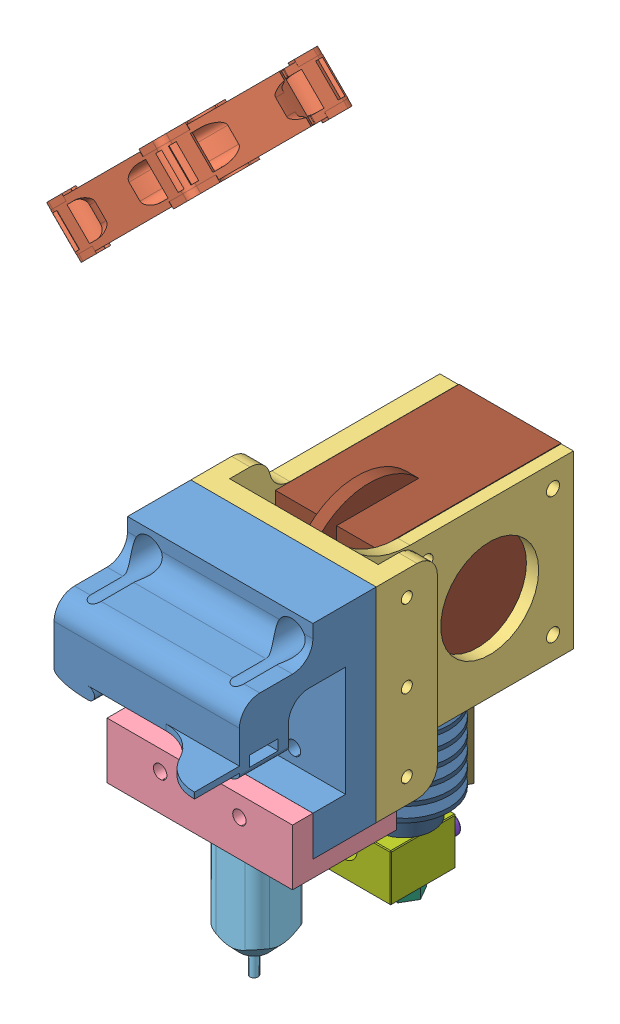
SolidWorks assembly Extruder Assembly, configuration Default. Lengths in mm.
Overall size (127.5 148.89 106).
17 component instances, 13 part files, 15 mates.
Components (placement in the parent):
- X Carriege Tool Mount-1: X Carriege Tool Mount [Default] at (45.4 75.1817 183.5817) x (-1 0 0) z (0 0 -1) size (45.42 50 44.5)
- Noctua-NF-A4x10-1: Noctua-NF-A4x10 [Default] at (-36.401 156.8138 129.5886) x (0 0 1) z (0.707107 -0.707107 0) size (40.06 40.06 12.26)
- Nema 17-1: Nema 17 [Default] at (72.7 96.1817 127.5817) x (0 1 0) z (-1 0 0) size (42 42 61)
- TItan Extruder Mount Simple v1-1: TItan Extruder Mount Simple v1 [Default] at (45.4 75.1817 168.0817) x (-1 0 0) z (0 0 -1) size (45.4 50 61)
- BL Touch Mount-1: BL Touch Mount [Default] at (-27.8645 -78.7405 -106.5513) size (45.4 56.15 32.72)
  - BL Touch Mount v2-1: BL Touch Mount v2 [Default] at (27.8645 153.9222 269.633) x (1 0 0) z (0 0 -1) size (45.4 13.75 25.5)
  - BL-touch-1: BL-touch [Predeterminado] at (44.1413 149.9222 275.4167) x (-1 0 0) z (0 1 0) size (26 26 42.4)
- E3D Titan Extruder-1: E3D Titan Extruder [Default] at (87.1521 59.5503 115.323) x (0 0 1) z (-1 0 0) size (54 96.06 28.75)
  - p_E3D.V6-1.75mm_0.3Nozzle_wPushIn_Bowden_-1: p_E3D.V6-1.75mm_0.3Nozzle_wPushIn_Bowden_ [Défaut] at (16.7586 -33.2186 70.9521) x (0 0 1) z (-1 0 0) size (27.2 60.7 23.91)
    - Nozzle 0.3mm^p_E3D.V6-1.75mm_0.3Nozzle_wPushIn_Bowden_-1: Nozzle 0.3mm^p_E3D.V6-1.75mm_0.3Nozzle_wPushIn_Bowden_ [Défaut] at origin size (8.08 13.04 7) (virtual)
    - Heater_Block^p_E3D.V6-1.75mm_0.3Nozzle_wPushIn_Bowden_-1: Heater_Block^p_E3D.V6-1.75mm_0.3Nozzle_wPushIn_Bowden_ [Défaut] at (0 5 0) x (1 0 0) z (0 1 0) size (20 16 11.5) (virtual)
    - socket head cap screw_din-3: socket head cap screw_din [DIN 912 M2 x 12 --- 12C] at (13.25 3 0) x (0 1 0) z (0 0 1) size (14 3.8 3.8)
    - socket head cap screw_din-4: socket head cap screw_din [DIN 912 M2.5 x 4 --- 4C] at (-1.25 11.5 10.5) x (0 0 -1) z (1 0 0) size (6.5 4.5 4.5)
    - Heatbreak^p_E3D.V6-1.75mm_0.3Nozzle_wPushIn_Bowden_-1: Heatbreak^p_E3D.V6-1.75mm_0.3Nozzle_wPushIn_Bowden_ [Défaut] at (0 12.5 0) x (0.99999 0 0.004447) z (-0.004447 0 0.99999) size (7.01 23.53 7.2) (virtual)
    - Heatsink^p_E3D.V6-1.75mm_0.3Nozzle_wPushIn_Bowden_-1: Heatsink^p_E3D.V6-1.75mm_0.3Nozzle_wPushIn_Bowden_ [Défaut] at (0 60.7 0) x (-0.995869 0 -0.090804) z (-0.090804 0 0.995869) size (22 42.7 22) (virtual)
  - Extruder Block-1: Extruder Block [Default] at (14.2586 36.7814 57.4521) size (54 47.06 25)
- Cooling Fan Mount v1-1: Cooling Fan Mount v1 [Default] at (16.2 48.6639 132.0817) x (-1 0 0) z (0 0 -1) size (25.84 41.08 40)
Mates (geometry in assembly coordinates):
- Coincident408: coincident anti-aligned: plane of X Carriege Tool Mount-1 through (45.4 75.1817 168.0817) normal (0 0 -1); plane of TItan Extruder Mount Simple v1-1 through (45.4 75.1817 168.0817) normal (0 0 1)
- Concentric134: concentric aligned: cylinder of X Carriege Tool Mount-1 through (40.2 120.1817 212.5817) axis (0 0 -1) radius 1.7; cylinder of TItan Extruder Mount Simple v1-1 through (40.2 120.1817 173.0817) axis (0 0 -1) radius 1.35
- Concentric135: concentric aligned: cylinder of X Carriege Tool Mount-1 through (5.2 120.1817 212.5817) axis (0 0 -1) radius 1.7; cylinder of TItan Extruder Mount Simple v1-1 through (5.2 120.1817 173.0817) axis (0 0 -1) radius 1.35
- Coincident414: coincident anti-aligned: plane of Nema 17 Small-1 through (32.7 96.1817 127.5817) normal (-1 0 0); plane of TItan Extruder Mount Simple v1-1 through (32.7 75.1817 107.0817) normal (1 0 0)
- Concentric136: concentric anti-aligned: cylinder of Nema 17 Small-1 through (72.7 80.6817 112.0817) axis (-1 0 0) radius 1.5; cylinder of TItan Extruder Mount Simple v1-1 through (-9.3 80.6817 112.0817) axis (1 0 0) radius 1.6
- Concentric137: concentric anti-aligned: cylinder of Nema 17 Small-1 through (72.7 111.6817 143.0817) axis (-1 0 0) radius 1.5; cylinder of TItan Extruder Mount Simple v1-1 through (-9.3 111.6817 143.0817) axis (1 0 0) radius 1.6
- Coincident409: coincident anti-aligned: plane of X Carriege Tool Mount-1 through (45.4 75.1817 183.5817) normal (0 0 1); plane of BL Touch Mount-1/BL Touch Mount v2-1 through (45.4 84.9317 183.5817) normal (0 0 -1)
- Coincident410: coincident anti-aligned: plane of X Carriege Tool Mount-1 through (45.4 75.1817 168.0817) normal (0 -1 0); plane of BL Touch Mount-1/BL Touch Mount v2-1 through (0 75.1817 163.0817) normal (0 1 0)
- Coincident411: coincident aligned: plane of X Carriege Tool Mount-1 through (0 75.1817 168.0817) normal (-1 0 0); plane of BL Touch Mount-1/BL Touch Mount v2-1 through (0 71.1817 163.0817) normal (-1 0 0)
- Coincident415: coincident anti-aligned: plane of E3D Titan Extruder-1/Extruder Block-1 through (29.7 96.3317 129.5817) normal (1 0 0); plane of TItan Extruder Mount Simple v1-1 through (29.7 75.1817 107.0817) normal (-1 0 0)
- Concentric138: concentric anti-aligned: cylinder of E3D Titan Extruder-1/Extruder Block-1 through (29.7 111.6817 143.0817) axis (-1 0 0) radius 1.5; cylinder of TItan Extruder Mount Simple v1-1 through (-9.3 111.6817 143.0817) axis (1 0 0) radius 1.6
- Concentric139: concentric anti-aligned: cylinder of E3D Titan Extruder-1/Extruder Block-1 through (29.7 80.6817 112.0817) axis (-1 0 0) radius 1.5; cylinder of TItan Extruder Mount Simple v1-1 through (-9.3 80.6817 112.0817) axis (1 0 0) radius 1.6
- Concentric141: concentric aligned: cylinder of E3D Titan Extruder-1/p_E3D.V6-1.75mm_0.3Nozzle_wPushIn_Bowden_-1/Heatsink^p_E3D.V6-1.75mm_0.3Nozzle_wPushIn_Bowden_-1 through (16.2 53.7717 132.0817) axis (0 1 0) radius 11; cylinder of Cooling Fan Mount v1-1 through (16.2 48.6639 132.0817) axis (0 1 0) radius 11
- Parallel3: parallel aligned: plane of TItan Extruder Mount Simple v1-1 through (0 75.1817 163.0817) normal (-1 0 0); plane of Cooling Fan Mount v1-1 through (-3.3 48.6639 132.0817) normal (-1 0 0)
- Coincident423: coincident anti-aligned: plane of X Carriege Tool Mount-1 through (0 75.1817 168.0817) normal (-1 0 0)
